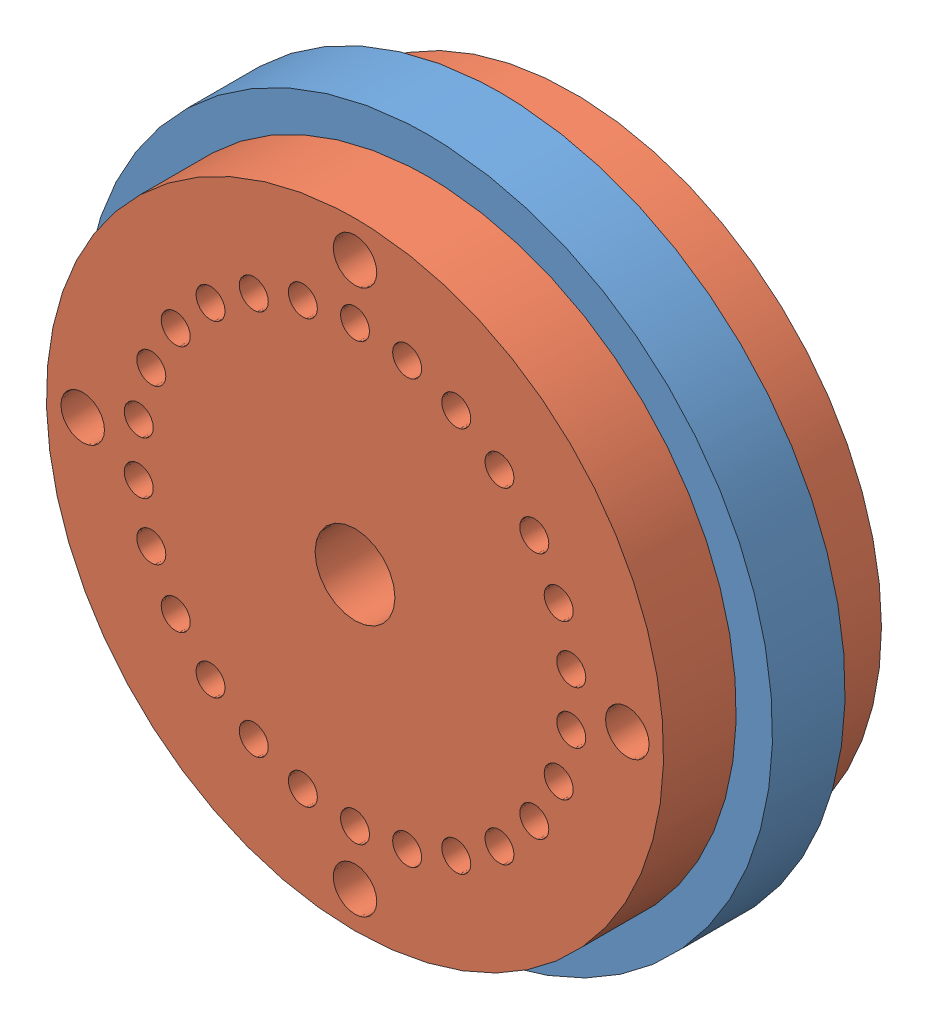
SolidWorks assembly Assemblage1, configuration Défaut. Lengths in mm.
Overall size (9.5 9.5 3).
3 component instances, 2 part files, 3 mates.
Components (placement in the parent):
- pignon sans pigon-1: pignon sans pigon [Défaut] at (0 0 3.1162) x (0 1 0) z (0 0 1) size (9.5 9.5 1)
- rotor-1: rotor [Défaut] at (0 0 5.1162) x (1 0 0) z (0 1 0) size (8.5 1 8.5)
- rotor-2: rotor [Défaut] at (0 0 3.1162) x (0 1 0) z (-1 0 0) size (8.5 1 8.5)
Mates (geometry in assembly coordinates):
- Coïncidente1: coincident anti-aligned: circle of pignon sans pigon-1; circle of rotor-2
- Coïncidente2: coincident anti-aligned: circle of pignon sans pigon-1; circle of rotor-2
- Coïncidente3: coincident anti-aligned: circle of pignon sans pigon-1; circle of rotor-1
